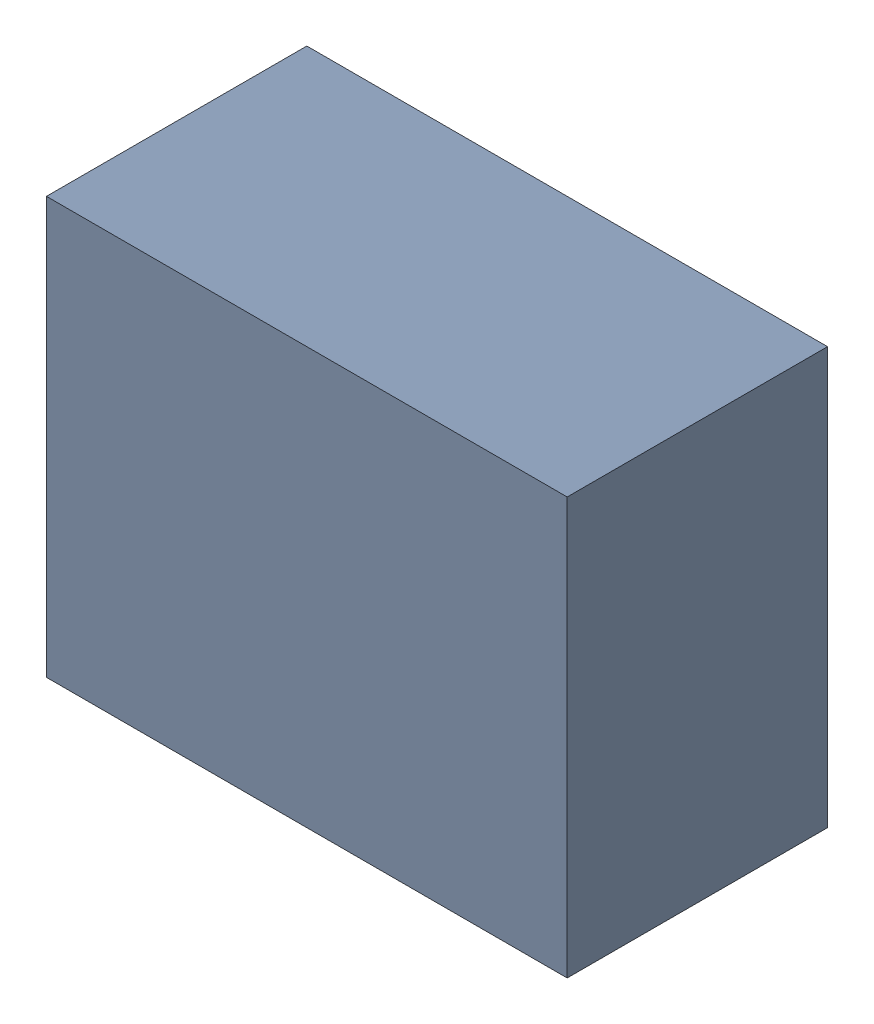
SolidWorks assembly D4, configuration Default. Lengths in mm.
Overall size (1 0.8 0.5).
2 component instances, 1 part files, 0 mates.
Components (placement in the parent):
- 870940960-1: 870940960 [Default] at (44.881 32.031 0) size (1 0.8 0.5)
  - Extruded_33-1: Extruded_33 [Default] at origin size (1 0.8 0.5)
